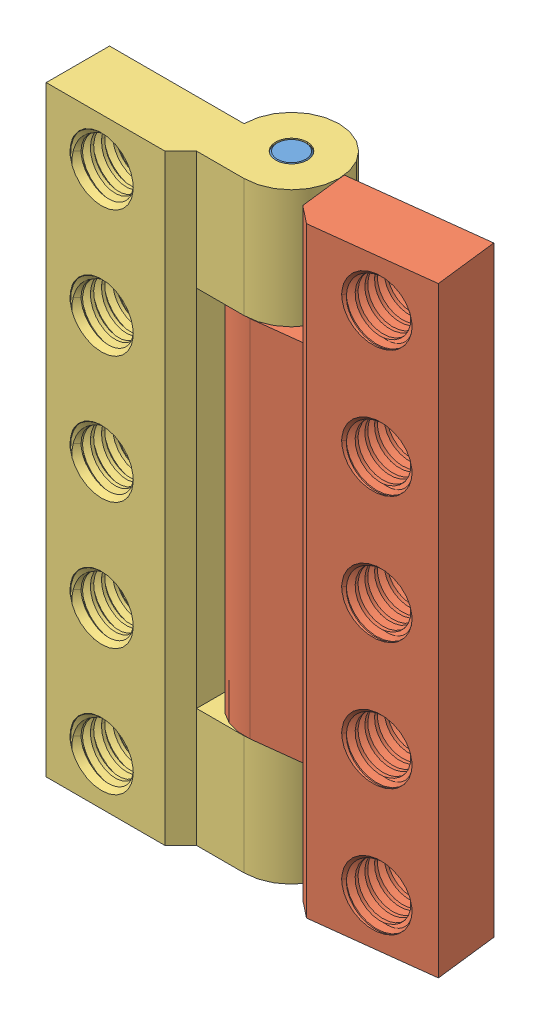
SolidWorks assembly Hinge-Assembly, configuration Default. Lengths in mm.
Overall size (23.39 38 8.67).
3 component instances, 3 part files, 4 mates.
Components (placement in the parent):
- M-D-007-Hinge Pin-1: M-D-007-Hinge Pin [Default] at (-149.7749 6.1799 75.3191) size (2 38 2)
- M-D-008-Hinge Flap 1-2: M-D-008-Hinge Flap 1 [Default] at (-151.8193 18.7921 80.2543) x (-0.992974 0 0.118332) z (0.118332 0 0.992974) size (14.5 38 7)
- M-D-009-Hinge Flap 2-2: M-D-009-Hinge Flap 2 [Default] at (-151.8193 -19.2079 80.2543) size (14.5 38 7)
Mates (geometry in assembly coordinates):
- Concentric1: concentric anti-aligned: cylinder of M-D-008-Hinge Flap 1-2 through (-151.8193 -19.2079 80.2543) axis (0 1 0) radius 1; cylinder of M-D-009-Hinge Flap 2-2 through (-151.8193 18.7921 80.2543) axis (0 -1 0) radius 1
- Coincident1: coincident anti-aligned: plane of M-D-008-Hinge Flap 1-2 through (-155.1532 -11.7079 77.6303) normal (0 -1 0); plane of M-D-009-Hinge Flap 2-2 through (-148.8193 -11.7079 77.2543) normal (0 1 0)
- Concentric2: concentric aligned: cylinder of M-D-007-Hinge Pin-1 through (-151.8193 18.7921 80.2543) axis (0 -1 0) radius 1; cylinder of M-D-009-Hinge Flap 2-2 through (-151.8193 18.7921 80.2543) axis (0 -1 0) radius 1
- Coincident2: coincident aligned: plane of M-D-007-Hinge Pin-1 through (-150.9193 18.7921 80.2543) normal (0 1 0); plane of M-D-009-Hinge Flap 2-2 through (-151.8193 18.7921 80.2543) normal (0 1 0)
